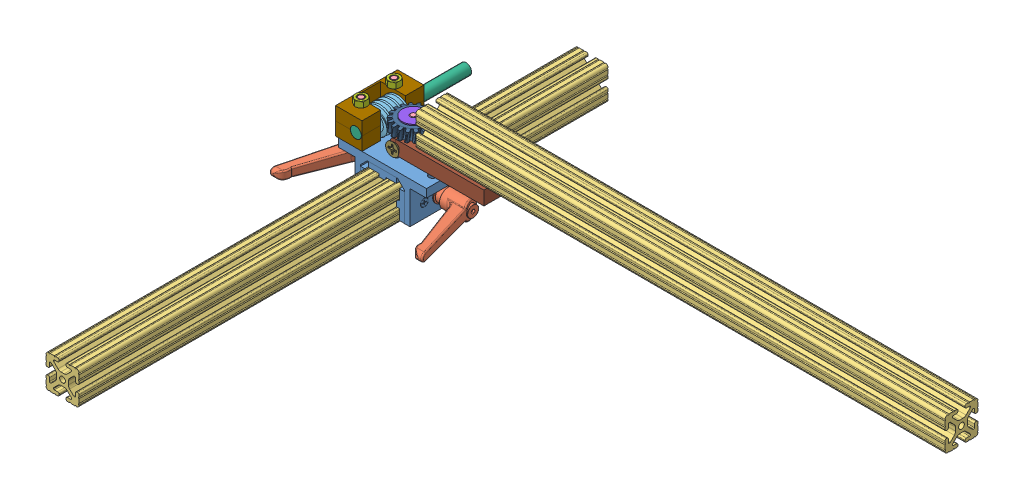
SolidWorks assembly Assembly_main_body_1_2, configuration Default. Lengths in mm.
Overall size (718.98 113.03 609.6).
20 component instances, 13 part files, 45 mates.
Components (placement in the parent):
- 47065T962_ALUMINUM T-SLOTTED FRAMING EXTRUSION-2: 47065T962_ALUMINUM T-SLOTTED FRAMING EXTRUSION [47065T962] at (8.4072 -361.078 1405.6293) size (101.6 47.62 71.42)
- 60585K320_LINEAR BEARING FOR T-SLOTTED FRAMING-4: 60585K320_LINEAR BEARING FOR T-SLOTTED FRAMING [60585K32] at (-32.2328 -345.203 1405.6293) x (-1 0 0) z (0 -1 0) size (75.81 88.77 38.39)
- 60585K320_LINEAR BEARING FOR T-SLOTTED FRAMING-5: 60585K320_LINEAR BEARING FOR T-SLOTTED FRAMING [60585K32] at (49.0472 -345.203 1405.6293) x (1 0 0) z (0 1 0) size (75.81 88.77 38.39)
- 47065T210_ALUMINUM T-SLOTTED FRAMING EXTRUSION-1: 47065T210_ALUMINUM T-SLOTTED FRAMING EXTRUSION [47065T21] at (8.4072 -345.203 1505.057) size (38.1 38.1 609.6)
- 90273A501_ZINC-PLATED STL FLAT HEAD PHIL MACHINE SCREW-1: 90273A501_ZINC-PLATED STL FLAT HEAD PHIL MACHINE SCREW [90273A501] at (8.4072 -328.975 1405.6293) x (1 0 0) z (0 -1 0) size (15.16 15.16 51.5)
- 90273A501_ZINC-PLATED STL FLAT HEAD PHIL MACHINE SCREW-2: 90273A501_ZINC-PLATED STL FLAT HEAD PHIL MACHINE SCREW [90273A501] at (-32.8678 -322.0566 1386.5793) x (1 0 0) z (0 -1 0) size (15.16 15.16 51.5)
- 90273A501_ZINC-PLATED STL FLAT HEAD PHIL MACHINE SCREW-3: 90273A501_ZINC-PLATED STL FLAT HEAD PHIL MACHINE SCREW [90273A501] at (-32.8678 -322.2903 1424.6793) x (1 0 0) z (0 -1 0) size (15.16 15.16 51.5)
- 57545K527_SPEED-REDUCING WORM GEAR FOR 90 DEG TRANSFER-1: 57545K527_SPEED-REDUCING WORM GEAR FOR 90 DEG TRANSFER [57545K527] at (-22.1092 -298.1352 1405.6293) x (-0.999997 -0.002405 0) z (0 0 -1) size (31.13 29.72 30.93)
- ATM_worm_shaft-2: ATM_worm_shaft [Default] at (-22.1998 -298.213 1441.2825) x (0.999997 0.002405 0) z (0 0 -1) size (12.65 13.45 127)
- 95505A602_GRADE 5 STEEL HEX NUT-1: 95505A602_GRADE 5 STEEL HEX NUT [95505A602] at (-32.8678 -279.5995 1424.6793) x (1 0 0) z (0 -1 0) size (12.7 14.66 8.63)
- 95505A602_GRADE 5 STEEL HEX NUT-3: 95505A602_GRADE 5 STEEL HEX NUT [95505A602] at (-32.8678 -279.5995 1386.5793) x (-0.546944 0 0.837169) z (0 1 0) size (12.7 14.66 8.63)
- ATM_part1-4: ATM_part1 [Default] at (8.4072 -283.608 1405.6293) x (1 0 0) z (0 0 -1) size (25.4 29.84 25.4)
- ATM_worm_case_R_update-1: ATM_worm_case_R_update [Default] at (-45.5678 -298.213 1405.6293) x (0 0 1) z (0 1 0) size (71.44 30.48 15.24)
- ATM_worm_case_R_update-2: ATM_worm_case_R_update [Default] at (-45.5678 -298.213 1405.6293) x (0 0 -1) z (0 -1 0) size (71.44 30.48 15.24)
- 57545K511_SPEED-REDUCING WORM GEAR FOR 90 DEG TRANSFER_Mod-3: 57545K511_SPEED-REDUCING WORM GEAR FOR 90 DEG TRANSFER_Mod [57545K511] at (8.4072 -291.228 1405.6293) x (1 0 0) z (0 0 -1) size (44.78 28.61 44.18)
- ATM_part2_Update-2: ATM_part2_Update [Default] at (59.2072 -313.1482 1405.6293) x (1 0 0) z (0 1 0) size (122.27 40.64 15.9)
- 90273A432_STEEL PHILLIPS FLAT HEAD SCREWS-5: 90273A432_STEEL PHILLIPS FLAT HEAD SCREWS [90273A432] at (8.4072 -305.198 1425.2023) size (15.16 15.16 16.37)
- 90273A432_STEEL PHILLIPS FLAT HEAD SCREWS-7: 90273A432_STEEL PHILLIPS FLAT HEAD SCREWS [90273A432] at (8.4072 -305.198 1385.9844) x (-1 0 0) z (0 0 -1) size (15.16 15.16 16.37)
- 47065T210_ALUMINUM T-SLOTTED FRAMING EXTRUSION-4: 47065T210_ALUMINUM T-SLOTTED FRAMING EXTRUSION [47065T21] at (334.6128 -278.1978 1405.134) x (0 0 -1) z (1 0 0) size (38.1 38.1 609.6)
- 47065T149_ALUMINUM T-SLOTTED FRAMING EXTRUSION-2: 47065T149_ALUMINUM T-SLOTTED FRAMING EXTRUSION [47065T149] at (76.9872 -307.1792 1405.6293) x (1 0 0) z (0 0 -1) size (71.37 22.44 16.84)
Mates (geometry in assembly coordinates):
- Concentric2: concentric anti-aligned: cylinder of 47065T962_ALUMINUM T-SLOTTED FRAMING EXTRUSION-2 through (-23.3428 -345.203 1405.6293) axis (1 0 0) radius 4.3561; cylinder of 60585K320_LINEAR BEARING FOR T-SLOTTED FRAMING-4 through (-32.2328 -345.203 1405.6293) axis (-1 0 0) radius 8.001
- Concentric3: concentric aligned: cylinder of 47065T962_ALUMINUM T-SLOTTED FRAMING EXTRUSION-2 through (-23.3428 -345.203 1405.6293) axis (1 0 0) radius 4.3561; cylinder of 60585K320_LINEAR BEARING FOR T-SLOTTED FRAMING-5 through (49.0472 -345.203 1405.6293) axis (1 0 0) radius 8.001
- Width10: width anti-aligned: plane of 47065T210_ALUMINUM T-SLOTTED FRAMING EXTRUSION-1 through (12.4712 -327.7066 1809.857) normal (-1 0 0); plane of 47065T962_ALUMINUM T-SLOTTED FRAMING EXTRUSION-2 through (4.3432 -328.6634 1809.857) normal (1 0 0); plane of 47065T210_ALUMINUM T-SLOTTED FRAMING EXTRUSION-1 through (12.3442 -325.899 1441.1893) normal (1 0 0); plane of 47065T962_ALUMINUM T-SLOTTED FRAMING EXTRUSION-2 through (4.4702 -325.899 1441.1893) normal (-1 0 0)
- Width11: width anti-aligned: plane of 47065T210_ALUMINUM T-SLOTTED FRAMING EXTRUSION-1 through (-8.1324 -349.267 1809.857) normal (0 1 0); plane of 47065T962_ALUMINUM T-SLOTTED FRAMING EXTRUSION-2 through (-9.0892 -341.139 1809.857) normal (0 -1 0); plane of 47065T210_ALUMINUM T-SLOTTED FRAMING EXTRUSION-1 through (-10.8968 -349.14 1441.1893) normal (0 -1 0); plane of 47065T962_ALUMINUM T-SLOTTED FRAMING EXTRUSION-2 through (-10.8968 -341.266 1441.1893) normal (0 1 0)
- Width12: width anti-aligned: plane of 47065T210_ALUMINUM T-SLOTTED FRAMING EXTRUSION-1 through (25.9036 -349.267 1809.857) normal (0 1 0); plane of 47065T962_ALUMINUM T-SLOTTED FRAMING EXTRUSION-2 through (24.9468 -341.139 1809.857) normal (0 -1 0); plane of 47065T210_ALUMINUM T-SLOTTED FRAMING EXTRUSION-1 through (27.7112 -349.14 1441.1893) normal (0 -1 0); plane of 47065T962_ALUMINUM T-SLOTTED FRAMING EXTRUSION-2 through (27.7112 -341.266 1441.1893) normal (0 1 0)
- Concentric4: concentric anti-aligned: cylinder of 47065T962_ALUMINUM T-SLOTTED FRAMING EXTRUSION-2 through (8.4072 -361.078 1405.6293) axis (0 1 0) radius 4.3561; circle of 90273A501_ZINC-PLATED STL FLAT HEAD PHIL MACHINE SCREW-1
- Lock5: lock: unknown of 47065T210_ALUMINUM T-SLOTTED FRAMING EXTRUSION-1; unknown of 90273A501_ZINC-PLATED STL FLAT HEAD PHIL MACHINE SCREW-1
- Concentric7: concentric aligned: cylinder of 47065T962_ALUMINUM T-SLOTTED FRAMING EXTRUSION-2 through (-32.8678 -361.078 1424.6793) axis (0 1 0) radius 4.1656; circle of 90273A501_ZINC-PLATED STL FLAT HEAD PHIL MACHINE SCREW-3
- Parallel11: parallel aligned: cylinder of 47065T962_ALUMINUM T-SLOTTED FRAMING EXTRUSION-2 through (-32.8678 -361.078 1424.6793) axis (0 1 0) radius 4.1656; line of 90273A501_ZINC-PLATED STL FLAT HEAD PHIL MACHINE SCREW-3 through (-32.8678 -327.1417 1424.6793) axis (0 1 0)
- Coincident18: coincident anti-aligned: plane of 47065T962_ALUMINUM T-SLOTTED FRAMING EXTRUSION-2 through (-42.3928 -322.978 1465.5218) normal (0 -1 0); circle of 90273A501_ZINC-PLATED STL FLAT HEAD PHIL MACHINE SCREW-3
- Concentric8: concentric aligned: cylinder of 47065T962_ALUMINUM T-SLOTTED FRAMING EXTRUSION-2 through (-32.8678 -361.078 1386.5793) axis (0 1 0) radius 4.1656; circle of 90273A501_ZINC-PLATED STL FLAT HEAD PHIL MACHINE SCREW-2
- Parallel12: parallel aligned: cylinder of 47065T962_ALUMINUM T-SLOTTED FRAMING EXTRUSION-2 through (-32.8678 -361.078 1386.5793) axis (0 1 0) radius 4.1656; line of 90273A501_ZINC-PLATED STL FLAT HEAD PHIL MACHINE SCREW-2 through (-32.8678 -326.908 1386.5793) axis (0 1 0)
- Coincident20: coincident aligned: cone of 47065T962_ALUMINUM T-SLOTTED FRAMING EXTRUSION-2; cone of 90273A501_ZINC-PLATED STL FLAT HEAD PHIL MACHINE SCREW-2 through (-32.8678 -326.908 1386.5793) axis (0 1 0)
- Perpendicular10: perpendicular: plane of 57545K527_SPEED-REDUCING WORM GEAR FOR 90 DEG TRANSFER-1 through (-23.7086 -293.1813 1421.1888) normal (0.999997 0.002405 0); plane of ATM_worm_shaft-2 through (-22.1998 -298.213 1391.3715) normal (0 0 -1)
- Lock6: lock: unknown of 57545K527_SPEED-REDUCING WORM GEAR FOR 90 DEG TRANSFER-1; unknown of ATM_worm_shaft-2
- Perpendicular12: perpendicular: plane of 57545K527_SPEED-REDUCING WORM GEAR FOR 90 DEG TRANSFER-1 through (-23.7086 -293.1813 1421.1888) normal (0.999997 0.002405 0); plane of ATM_worm_shaft-2 through (-23.8044 -291.0921 1391.3715) normal (-0.002405 0.999997 0)
- Concentric30: concentric aligned: circle of 90273A501_ZINC-PLATED STL FLAT HEAD PHIL MACHINE SCREW-2; circle of 95505A602_GRADE 5 STEEL HEX NUT-3
- Concentric31: concentric aligned: circle of 90273A501_ZINC-PLATED STL FLAT HEAD PHIL MACHINE SCREW-3; circle of 95505A602_GRADE 5 STEEL HEX NUT-1
- Tangent34: tangent: plane of 47065T962_ALUMINUM T-SLOTTED FRAMING EXTRUSION-2 through (-23.3428 -313.453 1441.3417) normal (0 1 0); circle of ATM_part1-4
- Concentric36: concentric anti-aligned: circle of 90273A501_ZINC-PLATED STL FLAT HEAD PHIL MACHINE SCREW-1; circle of ATM_part1-4
- Coincident22: coincident anti-aligned: plane of 47065T962_ALUMINUM T-SLOTTED FRAMING EXTRUSION-2 through (-23.3428 -313.453 1441.3417) normal (0 1 0); plane of ATM_worm_case_R_update-1 through (-15.0878 -313.453 1369.9106) normal (0 -1 0)
- Concentric37: concentric aligned: cylinder of 90273A501_ZINC-PLATED STL FLAT HEAD PHIL MACHINE SCREW-2 through (-32.8678 -326.908 1386.5793) axis (0 -1 0) radius 3.9624; circle of ATM_worm_case_R_update-1
- Concentric38: concentric anti-aligned: circle of ATM_worm_shaft-2; circle of ATM_worm_case_R_update-1
- Concentric39: concentric anti-aligned: circle of ATM_worm_shaft-2; circle of ATM_worm_case_R_update-1
- Coincident23: coincident anti-aligned: plane of 57545K527_SPEED-REDUCING WORM GEAR FOR 90 DEG TRANSFER-1 through (-8.839 -298.1033 1391.3418) normal (0 0 -1); plane of ATM_worm_case_R_update-1 through (-15.0878 -314.469 1391.3418) normal (0 0 1)
- Coincident24: coincident anti-aligned: plane of ATM_worm_case_R_update-1 through (-45.5678 -298.213 1405.6293) normal (0 1 0); plane of ATM_worm_case_R_update-2 through (-45.5678 -298.213 1405.6293) normal (0 -1 0)
- Concentric40: concentric aligned: circle of 90273A501_ZINC-PLATED STL FLAT HEAD PHIL MACHINE SCREW-3; cylinder of ATM_worm_case_R_update-2 through (-32.8678 -282.973 1424.6793) axis (0 1 0) radius 3.2639
- Concentric41: concentric aligned: circle of 90273A501_ZINC-PLATED STL FLAT HEAD PHIL MACHINE SCREW-2; cylinder of ATM_worm_case_R_update-2 through (-32.8678 -282.973 1386.5793) axis (0 1 0) radius 3.2639
- Coincident25: coincident anti-aligned: plane of 95505A602_GRADE 5 STEEL HEX NUT-1 through (-39.2178 -282.973 1428.3455) normal (0 -1 0); plane of ATM_worm_case_R_update-2 through (-15.0878 -282.973 1441.3481) normal (0 1 0)
- Coincident26: coincident anti-aligned: plane of 95505A602_GRADE 5 STEEL HEX NUT-3 through (-26.3255 -282.973 1383.2685) normal (0 -1 0); plane of ATM_worm_case_R_update-2 through (-15.0878 -282.973 1441.3481) normal (0 1 0)
- Coincident27: coincident anti-aligned: plane of 47065T962_ALUMINUM T-SLOTTED FRAMING EXTRUSION-2 through (-23.3428 -313.453 1441.3417) normal (-1 0 0); plane of 60585K320_LINEAR BEARING FOR T-SLOTTED FRAMING-4 through (-23.3428 -345.203 1405.6293) normal (1 0 0)
- Coincident28: coincident anti-aligned: plane of 47065T962_ALUMINUM T-SLOTTED FRAMING EXTRUSION-2 through (40.1572 -313.453 1441.3417) normal (1 0 0); plane of 60585K320_LINEAR BEARING FOR T-SLOTTED FRAMING-5 through (40.1572 -345.203 1405.6293) normal (-1 0 0)
- Concentric58: concentric aligned: cylinder of 57545K511_SPEED-REDUCING WORM GEAR FOR 90 DEG TRANSFER_Mod-3 through (8.4072 -305.198 1388.6113) axis (0 0 1) radius 3.2639; cylinder of ATM_part2_Update-2 through (8.4072 -305.198 1425.9493) axis (0 0 1) radius 3.2639
- Concentric59: concentric aligned: cylinder of 57545K511_SPEED-REDUCING WORM GEAR FOR 90 DEG TRANSFER_Mod-3 through (8.4072 -231.228 1405.6293) axis (0 -1 0) radius 15.875; cylinder of ATM_part2_Update-2 through (8.4072 -294.7078 1405.6293) axis (0 -1 0) radius 15.9004
- Concentric60: concentric anti-aligned: circle of ATM_part2_Update-2; circle of 90273A432_STEEL PHILLIPS FLAT HEAD SCREWS-5
- Concentric61: concentric aligned: circle of ATM_part2_Update-2; circle of 90273A432_STEEL PHILLIPS FLAT HEAD SCREWS-7
- Lock10: lock: unknown of 57545K511_SPEED-REDUCING WORM GEAR FOR 90 DEG TRANSFER_Mod-3; unknown of 90273A432_STEEL PHILLIPS FLAT HEAD SCREWS-7
- Lock11: lock: unknown of 57545K511_SPEED-REDUCING WORM GEAR FOR 90 DEG TRANSFER_Mod-3; unknown of 90273A432_STEEL PHILLIPS FLAT HEAD SCREWS-5
- Coincident42: coincident anti-aligned: plane of ATM_part2_Update-2 through (8.4072 -297.2478 1405.6293) normal (0 1 0); plane of 47065T210_ALUMINUM T-SLOTTED FRAMING EXTRUSION-4 through (639.4128 -297.2478 1419.4617) normal (0 -1 0)
- Concentric62: concentric anti-aligned: circle of ATM_part2_Update-2; circle of 47065T149_ALUMINUM T-SLOTTED FRAMING EXTRUSION-2
- Coincident44: coincident anti-aligned: plane of ATM_part2_Update-2 through (100.2536 -307.1792 1405.6293) normal (0 -1 0); plane of 47065T149_ALUMINUM T-SLOTTED FRAMING EXTRUSION-2 through (104.4573 -307.1792 1405.6293) normal (0 1 0)
- Tangent73: tangent anti-aligned: plane of 47065T210_ALUMINUM T-SLOTTED FRAMING EXTRUSION-4 through (639.4128 -294.7374 1401.07) normal (0 0 1); cylinder of 47065T149_ALUMINUM T-SLOTTED FRAMING EXTRUSION-2 through (96.0372 -295.1904 1405.6293) axis (0 -1 0) radius 4.5593
- Lock12: lock: unknown of ATM_part2_Update-2; unknown of 47065T210_ALUMINUM T-SLOTTED FRAMING EXTRUSION-4
- Concentric63: concentric aligned: cylinder of ATM_part1-4 through (8.4072 -313.453 1405.6293) axis (0 1 0) radius 6.096; cylinder of 57545K511_SPEED-REDUCING WORM GEAR FOR 90 DEG TRANSFER_Mod-3 through (8.4072 -223.7993 1405.6293) axis (0 1 0) radius 6.35
- Coincident46: coincident anti-aligned: plane of ATM_part1-4 through (8.4072 -284.878 1405.6293) normal (0 -1 0); plane of 57545K511_SPEED-REDUCING WORM GEAR FOR 90 DEG TRANSFER_Mod-3 through (8.4072 -284.878 1405.6293) normal (0 1 0)
